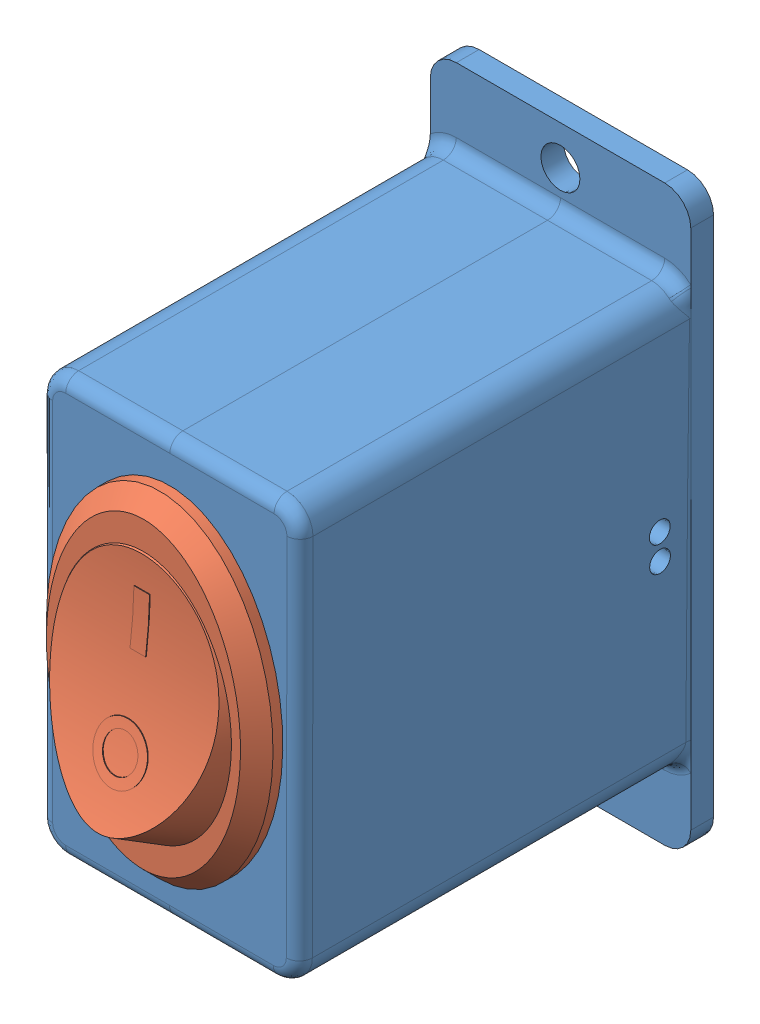
SolidWorks assembly SwitchONOFF, configuration Défaut. Lengths in mm.
Overall size (20.2 44.05 37.95).
2 component instances, 2 part files, 2 mates.
Components (placement in the parent):
- ButtonSwitch-1: ButtonSwitch [Défaut] at (-106.3372 -65.9682 59.7776) size (20.2 44.05 32.84)
- Switch R13112ABB-1: Switch R13112ABB [Default] at (-0.9254 -0.5715 59.7776) x (1 -0.000956 0) z (0 0 1) size (17.6 26 28.8)
Mates (geometry in assembly coordinates):
- Coïncidente1: coincident anti-aligned: plane of ButtonSwitch-1 through (-106.3372 -65.9682 59.7776) normal (0 0 1); plane of Switch R13112ABB-1 through (-0.9254 -0.5715 59.7776) normal (0 0 -1)
- Coïncidente2: coincident anti-aligned: line of ButtonSwitch-1 through (-9.8997 -0.5629 59.7776) axis (1 -0.000956 0); line of Switch R13112ABB-1 through (7.7746 -0.5798 59.7776) axis (-1 0.000956 0)
